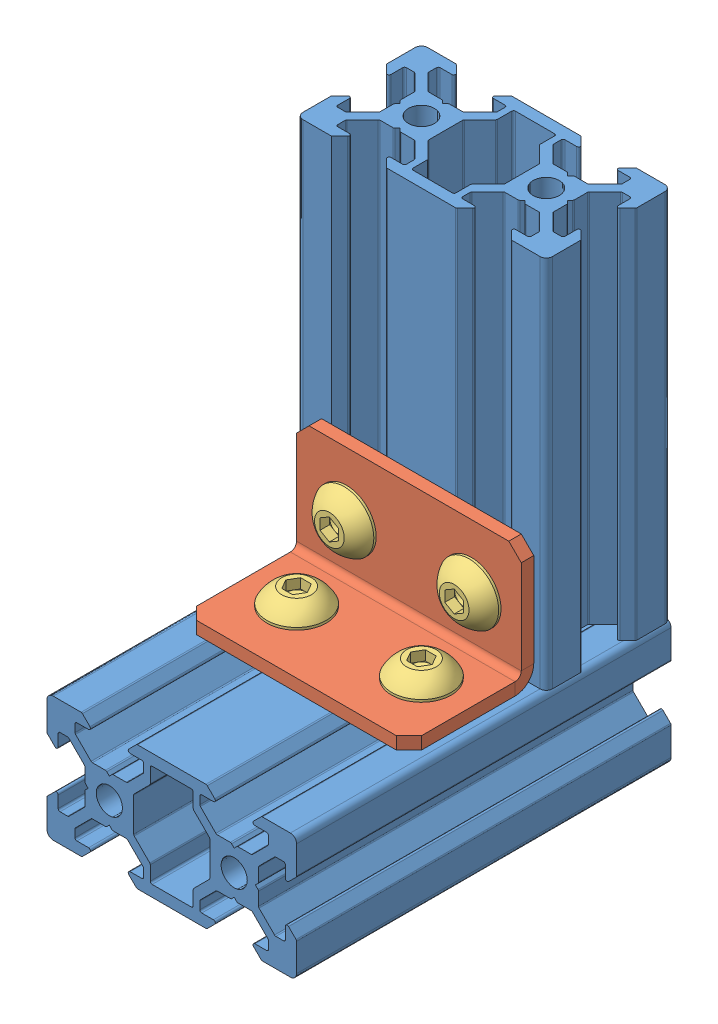
SolidWorks assembly Уголок 20 серия 2х2 20х20х36х2 СБ, configuration По умолчанию. Lengths in mm.
Overall size (40 80 60).
7 component instances, 3 part files, 14 mates.
Components (placement in the parent):
- 204090-1: 204090 [По умолчанию] at origin size (40 20 60)
- 204090-2: 204090 [По умолчанию] at (0 10 10) x (1 0 0) z (0 1 0) size (40 20 60)
- Уголок 20 серия 2х2 20х20х36х2-1: Уголок 20 серия 2х2 20х20х36х2 [По умолчанию] at (10 10 20) size (36 20 20)
- socket button head screw_iso-1: socket button head screw_iso [ISO 7380 - M5 x 10 - 10N] at (0 20 24.75) x (0 0 -1) z (1 0 0) size (12.75 9.5 9.5)
- socket button head screw_iso-2: socket button head screw_iso [ISO 7380 - M5 x 10 - 10N] at (20 20 24.75) x (0 0 -1) z (1 0 0) size (12.75 9.5 9.5)
- socket button head screw_iso-3: socket button head screw_iso [ISO 7380 - M5 x 10 - 10N] at (0 14.75 30) x (0 -1 0) z (0 0 1) size (12.75 9.5 9.5)
- socket button head screw_iso-4: socket button head screw_iso [ISO 7380 - M5 x 10 - 10N] at (20 14.75 30) x (0 -1 0) z (0 0 1) size (12.75 9.5 9.5)
Mates (geometry in assembly coordinates):
- Совпадение1: coincident aligned: plane of 204090-1 through (30 10 60) normal (1 0 0); plane of 204090-2 through (30 70 20) normal (1 0 0)
- Совпадение2: coincident anti-aligned: plane of 204090-1 through (30 10 60) normal (0 1 0); plane of 204090-2 through (0 10 10) normal (0 -1 0)
- Совпадение5: coincident aligned: plane of 204090-1 through (0 0 0) normal (0 0 -1); plane of 204090-2 through (30 70 0) normal (0 0 -1)
- Совпадение6: coincident anti-aligned: plane of 204090-1 through (15.6 10 60) normal (0 1 0); plane of Уголок 20 серия 2х2 20х20х36х2-1 through (10 10 20) normal (0 -1 0)
- Совпадение7: coincident anti-aligned: plane of 204090-2 through (15.6 70 20) normal (0 0 1); plane of Уголок 20 серия 2х2 20х20х36х2-1 through (10 10 20) normal (0 0 -1)
- Расстояние1: distance = 2 mm aligned: plane of Уголок 20 серия 2х2 20х20х36х2-1 through (28 10 40) normal (1 0 0); plane of 204090-1 through (30 10 60) normal (1 0 0)
- Концентричный1: concentric aligned: cylinder of Уголок 20 серия 2х2 20х20х36х2-1 through (0 20 22) axis (0 0 1) radius 2.75; cylinder of socket button head screw_iso-1 through (0 20 24.75) axis (0 0 1) radius 4.75
- Совпадение8: coincident anti-aligned: plane of Уголок 20 серия 2х2 20х20х36х2-1 through (10 10 22) normal (0 0 1); plane of socket button head screw_iso-1 through (0 22.5 22) normal (0 0 -1)
- Концентричный2: concentric aligned: cylinder of Уголок 20 серия 2х2 20х20х36х2-1 through (20 20 22) axis (0 0 1) radius 2.75; cylinder of socket button head screw_iso-2 through (20 20 24.75) axis (0 0 1) radius 4.75
- Совпадение9: coincident anti-aligned: plane of Уголок 20 серия 2х2 20х20х36х2-1 through (10 10 22) normal (0 0 1); plane of socket button head screw_iso-2 through (20 22.5 22) normal (0 0 -1)
- Концентричный3: concentric aligned: cylinder of Уголок 20 серия 2х2 20х20х36х2-1 through (0 12 30) axis (0 1 0) radius 2.75; cylinder of socket button head screw_iso-3 through (0 14.75 30) axis (0 1 0) radius 4.75
- Совпадение10: coincident anti-aligned: plane of Уголок 20 серия 2х2 20х20х36х2-1 through (10 12 20) normal (0 1 0); plane of socket button head screw_iso-3 through (2.5 12 30) normal (0 -1 0)
- Концентричный4: concentric aligned: cylinder of Уголок 20 серия 2х2 20х20х36х2-1 through (20 12 30) axis (0 1 0) radius 2.75; cylinder of socket button head screw_iso-4 through (20 14.75 30) axis (0 1 0) radius 4.75
- Совпадение11: coincident anti-aligned: plane of Уголок 20 серия 2х2 20х20х36х2-1 through (10 12 20) normal (0 1 0); plane of socket button head screw_iso-4 through (22.5 12 30) normal (0 -1 0)
